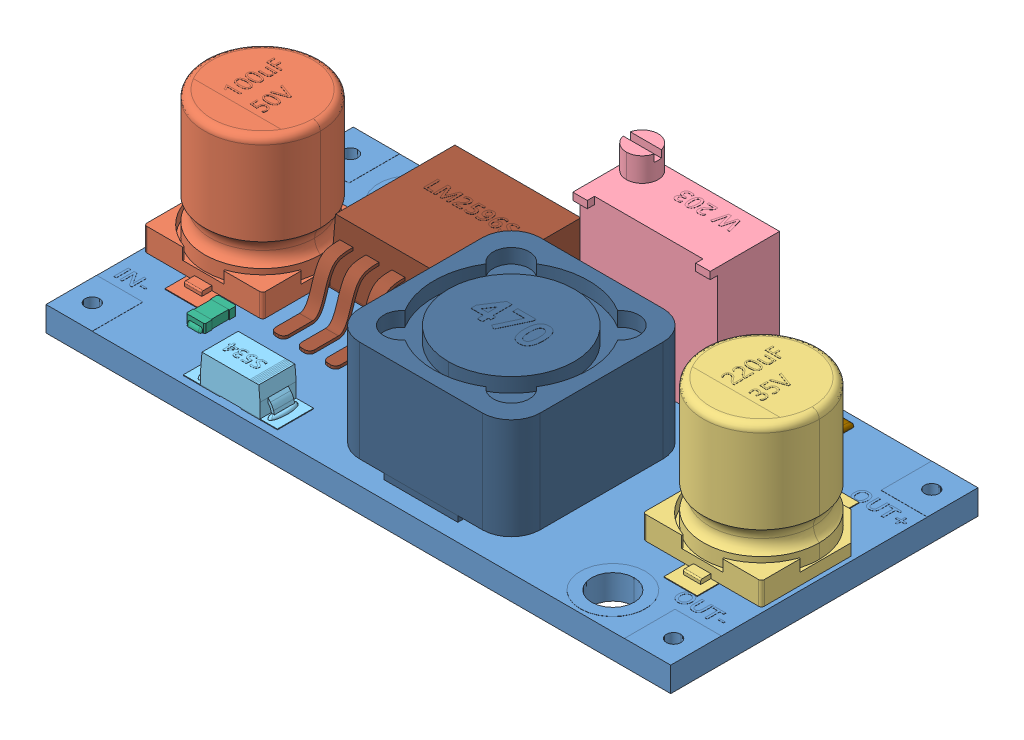
SolidWorks assembly LM2596 DC to DC Buck Converter 3 A, configuration Default. Lengths in mm.
Overall size (43.2 15.15 21.25).
12 component instances, 11 part files, 0 mates.
Components (placement in the parent):
- lm2596board-1: lm2596board [lm2596board] at origin size (43.2 1.71 21.25)
- smd100uF-1: smd100uF [smd100uF] at (-17.25 2.55 0) x (0 0 -1) z (1 0 0) size (11.2 9.76 8.2)
- smd220uF-1: smd220uF [smd220uF] at (17.25 2.55 0) x (0 0 -1) z (1 0 0) size (11.2 9.76 8.2)
- TrimmerW203-1: TrimmerW203 [TrimmerW203] at (4.6271 6.95 -9.1276) size (9.5 15.15 4.81)
- smdS537diode-1: smdS537diode [smdS537diode] at (-9.35 1.75 8.875) x (-1 0 0) z (0 0 -1) size (6.5 2.06 2.5)
- smdceramiccapacitor-1: smdceramiccapacitor [smdceramiccapacitor] at (-15 1.7 5.7969) x (0 0 1) z (-1 0 0) size (2.52 0.61 1.3)
- smdceramiccapacitor-2: smdceramiccapacitor [smdceramiccapacitor] at (-1.3196 1.7 -5.2916) x (0 0 1) z (-1 0 0) size (2.52 0.61 1.3)
- smdResistor331-1: smdResistor331 [smdResistor331] at (-1.2696 1.7 -8.4665) x (0 0 1) z (-1 0 0) size (2.53 0.63 1.31)
- smdResistor102-1: smdResistor102 [smdResistor102] at (10.7771 1.7 -8.4665) x (0 0 -1) z (1 0 0) size (2.53 0.63 1.31)
- smdLED-1: smdLED [smdLED] at (13.0521 1.75 -8.4701) x (0 0 -1) z (1 0 0) size (3.23 0.86 1.26)
- smbInductor470-1: smbInductor470 [smbInductor470] at (3.1271 2.1 3.175) size (12.5 7.41 12.5)
- LM2596S-1: LM2596S [LM2596S] at (-8.0627 1.8 -4.5407) size (9.8 4.61 14.95)
